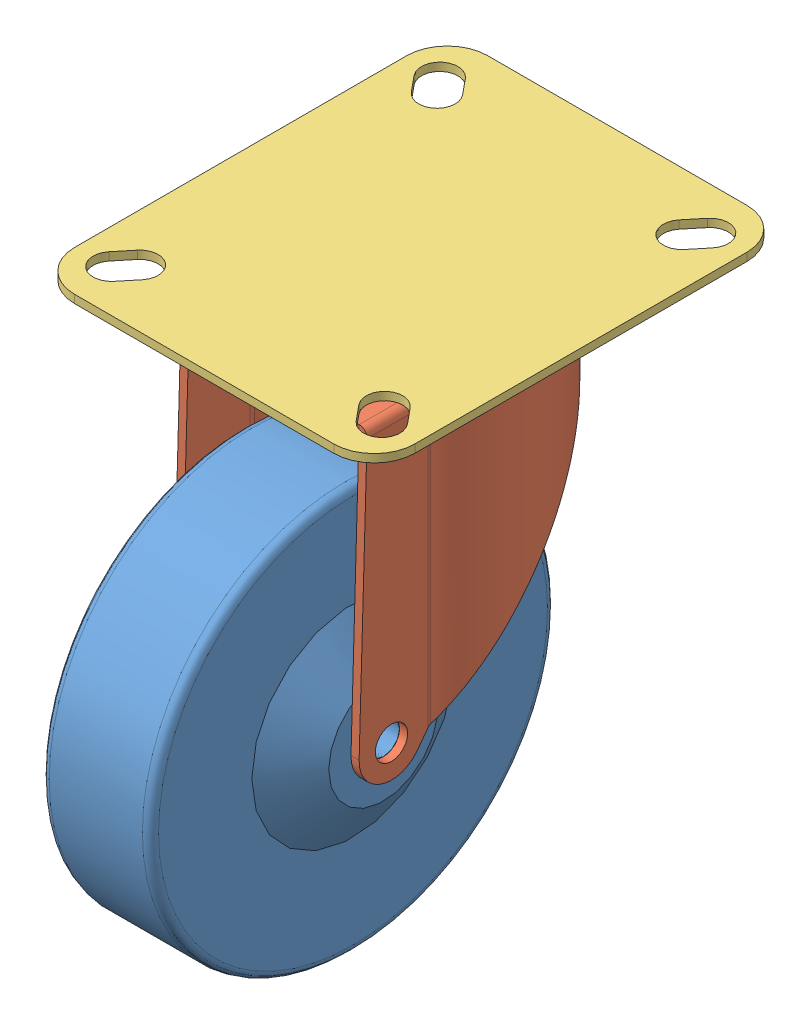
SolidWorks assembly Сборка1, configuration 00. Lengths in mm.
Overall size (84 130 128.76).
3 component instances, 3 part files, 8 mates.
Components (placement in the parent):
- Колесо 100мм-1: Колесо 100мм [--] at origin size (42 100 100)
- Поворотная скоба-1: Поворотная скоба [--] x (1 0 0) z (0 1 0) size (59 65.26 80)
- Опорная площадка-1: Опорная площадка [--] at (0 72 0) x (1 0 0) z (0 1 0) size (84 102 8)
Mates (geometry in assembly coordinates):
- На месте1: in place: plane of Поворотная скоба-1 through (0 0 0) normal (0 1 0); moOrthogonalPlaneRef_w of Поворотная скоба-1 through (0 0 0) normal (0 0 -1); plane of Поворотная скоба-1 through (0 0 0) normal (1 0 0); unknown of Поворотная скоба-1
- Совпадение1: coincident: plane of Поворотная скоба-1; plane of assembly
- Совпадение2: coincident: plane of Поворотная скоба-1 through (0 0 0) normal (0 0 -1); moOrthogonalPlaneRef_w of assembly
- Совпадение3: coincident: plane of Поворотная скоба-1 through (0 0 0) normal (1 0 0); moOrthogonalPlaneRef_w of assembly
- На месте2: in place: plane of Поворотная скоба-1 through (0 72 -27.7553) normal (0 1 0); plane of Опорная площадка-1 through (0 72 0) normal (0 1 0); plane of Поворотная скоба-1 through (0 72 -27.7553) normal (0 1 0); plane of Опорная площадка-1 through (0 72 0) normal (0 0 -1); plane of Поворотная скоба-1 through (0 72 -27.7553) normal (0 1 0); plane of Опорная площадка-1 through (0 72 0) normal (1 0 0); plane of Поворотная скоба-1 through (0 72 -27.7553) normal (0 1 0); unknown of Опорная площадка-1
- Совпадение4: coincident: plane of Поворотная скоба-1; plane of Опорная площадка-1
- Совпадение5: coincident: moOrthogonalPlaneRef_w of Поворотная скоба-1 through (0 72 0) normal (0 0 -1); plane of Опорная площадка-1 through (0 72 0) normal (0 0 -1)
- Совпадение6: coincident: moOrthogonalPlaneRef_w of Поворотная скоба-1 through (0 72 0) normal (-1 0 0); plane of Опорная площадка-1 through (0 72 0) normal (1 0 0)
